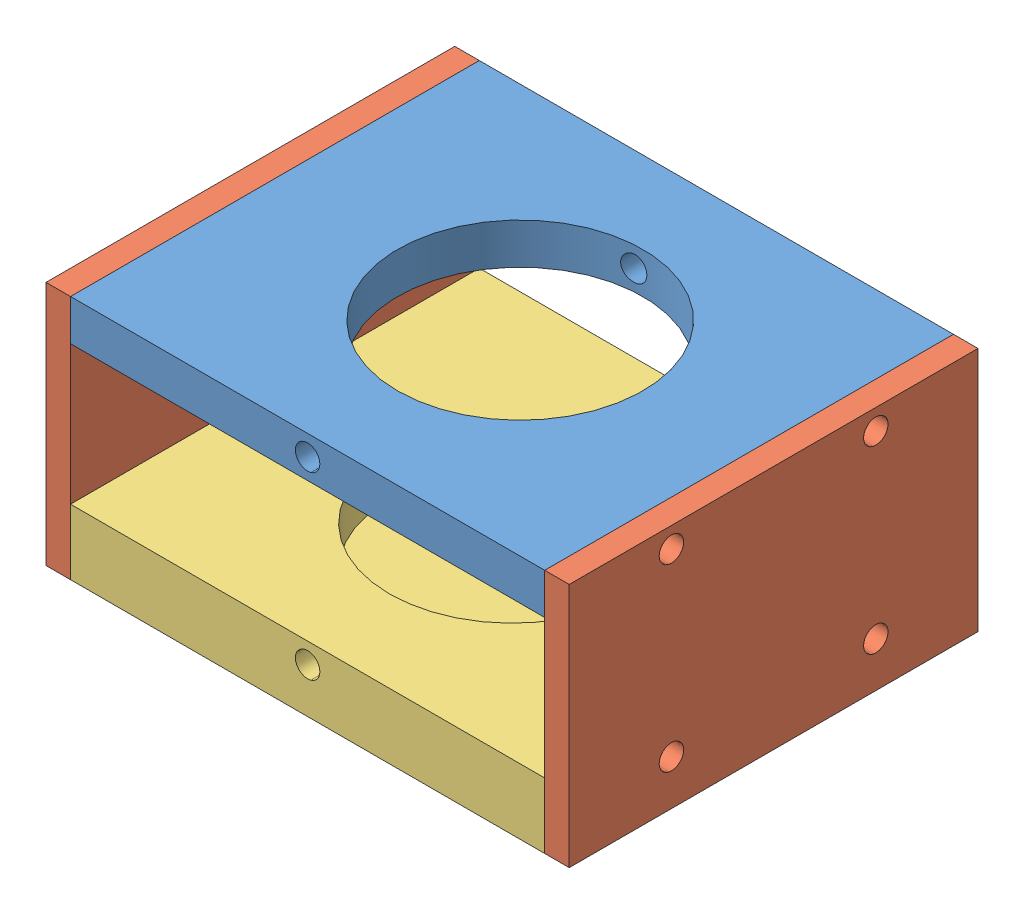
SolidWorks assembly Assemblage1, configuration Défaut. Lengths in mm.
Overall size (64 30 50).
4 component instances, 3 part files, 7 mates.
Components (placement in the parent):
- Carcasse - Copie-1: Carcasse - Copie [Défaut] at (-19.0672 55.4449 33) size (58 5 50)
- Côté_1_ext - Copie-1: Côté_1_ext - Copie [Défaut] at (36.4328 -5.1194 63.8602) x (0 0 1) z (-1 0 0) size (50 30 3)
- Support_axe_2-1: Support_axe_2 [Défaut] at (-19.0672 33.4449 33) size (58 8 50)
- Côté_1_ext - Copie-2: Côté_1_ext - Copie [Défaut] at (-27.5672 -5.1194 52.1398) x (0 0 -1) z (1 0 0) size (50 30 3)
Mates (geometry in assembly coordinates):
- Coaxiale5: concentric anti-aligned: circle of Carcasse - Copie-1; circle of Côté_1_ext - Copie-1
- Coaxiale6: concentric anti-aligned: circle of Carcasse - Copie-1; circle of Côté_1_ext - Copie-1
- Coïncidente7: coincident anti-aligned: plane of Carcasse - Copie-1 through (33.4328 10.4449 83) normal (1 0 0); plane of Côté_1_ext - Copie-1 through (33.4328 -5.1194 63.8602) normal (-1 0 0)
- Coaxiale10: concentric anti-aligned: cylinder of Côté_1_ext - Copie-1; cylinder of Support_axe_2-1 through (23.4328 -14.0551 45.5) axis (1 0 0) radius 1.5
- Coaxiale11: concentric anti-aligned: circle of Carcasse - Copie-1; circle of Côté_1_ext - Copie-2
- Coaxiale12: concentric aligned: circle of Support_axe_2-1; cylinder of Côté_1_ext - Copie-2 through (-24.5672 -14.0551 70.5) axis (-1 0 0) radius 1.5
- Coïncidente10: coincident anti-aligned: plane of Carcasse - Copie-1 through (-24.5672 10.4449 83) normal (-1 0 0); plane of Côté_1_ext - Copie-2 through (-24.5672 -5.1194 52.1398) normal (1 0 0)
